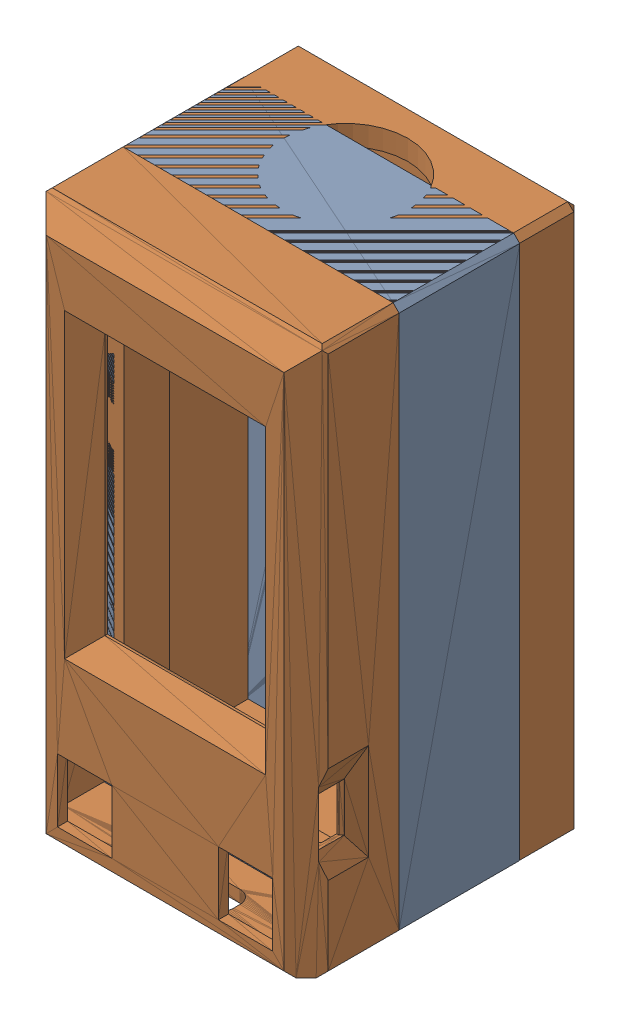
SolidWorks assembly calosc, configuration Domyślna. Lengths in mm.
Overall size (28.05 54.35 27.25).
3 component instances, 3 part files, 6 mates.
Components (placement in the parent):
- TTGO_T-Display_Box_-_Bottom_-_10mm_deep-1: TTGO_T-Display_Box_-_Bottom_-_10mm_deep [Domyślna] at (-21.0686 8.2021 0) size (28.05 54.35 14.5) (hidden)
- TTGO_T-Display_Box_-_Top-1: TTGO_T-Display_Box_-_Top [Domyślna] at (-21.0686 8.2021 0) size (28.05 54.35 9.25)
- obudowa_dolna-1: obudowa_dolna [Domyślna] at (-21.0686 8.2021 -23) x (0 1 0) z (1 0 0) size (54.35 20.5 28)
Mates (geometry in assembly coordinates):
- Wspólnie1: coincident anti-aligned: plane of TTGO_T-Display_Box_-_Bottom_-_10mm_deep-1 through (-8.2436 8.2021 0) normal (1 0 0); plane of TTGO_T-Display_Box_-_Top-1 through (-8.2436 8.2021 0) normal (-1 0 0)
- Wspólnie2: coincident anti-aligned: plane of TTGO_T-Display_Box_-_Bottom_-_10mm_deep-1 through (-21.0686 8.2021 -5) normal (0 0 1); plane of TTGO_T-Display_Box_-_Top-1 through (-21.0686 8.2021 -5) normal (0 0 -1)
- Wspólnie3: coincident anti-aligned: plane of TTGO_T-Display_Box_-_Bottom_-_10mm_deep-1 through (-21.0686 34.1771 0) normal (0 1 0); plane of TTGO_T-Display_Box_-_Top-1 through (-21.0686 34.1771 0) normal (0 -1 0)
- Wspólnie4: coincident anti-aligned: plane of TTGO_T-Display_Box_-_Top-1 through (-8.2436 8.2021 0) normal (-1 0 0); plane of obudowa_dolna-1 through (-8.2436 34.1771 -2.5) normal (1 0 0)
- Wspólnie5: coincident anti-aligned: plane of TTGO_T-Display_Box_-_Top-1 through (-21.0686 34.1771 0) normal (0 -1 0); plane of obudowa_dolna-1 through (-8.2436 34.1771 -2.5) normal (0 1 0)
- Wspólnie6: coincident anti-aligned: plane of TTGO_T-Display_Box_-_Top-1 through (-21.0686 8.2021 -5) normal (0 0 -1); plane of obudowa_dolna-1 through (-21.0686 8.2021 -5) normal (0 0 1)
